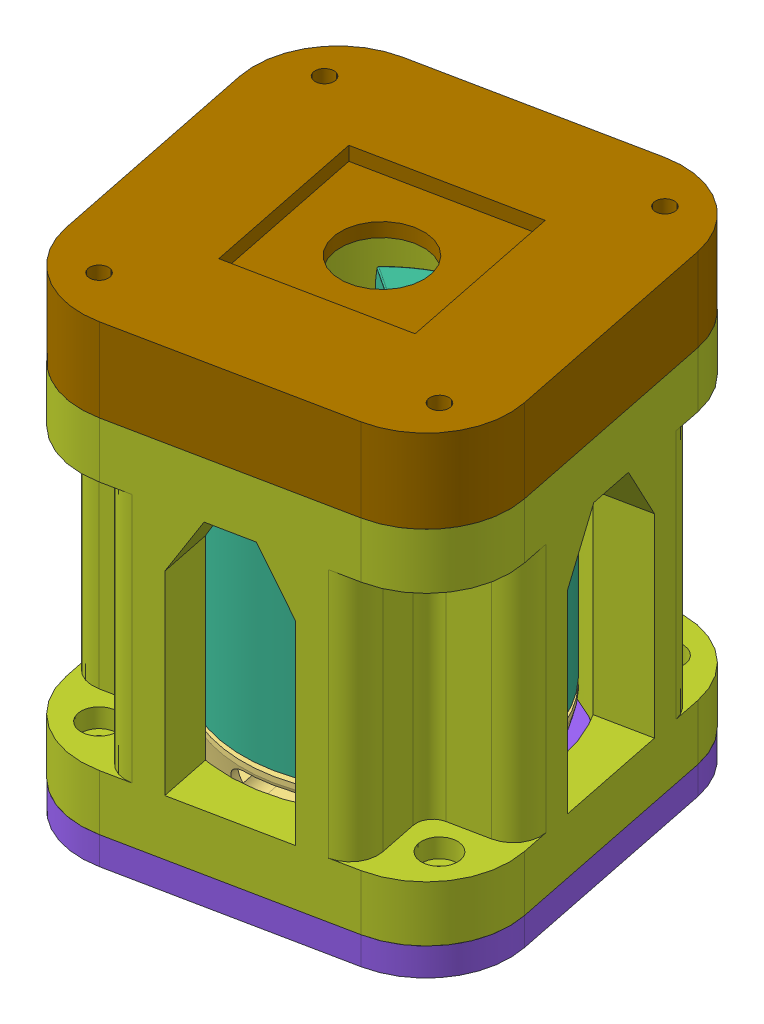
SolidWorks assembly Cheap 5065, configuration Default. Lengths in mm.
Overall size (82.53 103.1 82.53).
119 component instances, 9 part files, 14 mates.
Components (placement in the parent):
- Cheap 5065.step-1: Cheap 5065.step [Default] at (0 82 0) x (0.199009 0 0.979998) z (-0.979998 0 0.199009) size (50 84 50)
  - Stator.step-1: Stator.step [Default] at (0 -45.9 0) size (40 38 40)
    - Coils.step-1: Coils.step [Default] at origin size (4.5 38 8)
      - Copper Coil.step-1: Copper Coil.step [Default] at (0 0 -0.5) size (4.5 38 1)
      - Copper Coil.step-2: Copper Coil.step [Default] at (0 0 -2.5) size (4.5 38 1)
      - Copper Coil.step-3: Copper Coil.step [Default] at (0 0 -6.5) size (4.5 38 1)
      - Copper Coil.step-4: Copper Coil.step [Default] at (0 0 -1.5) size (4.5 38 1)
      - Copper Coil.step-5: Copper Coil.step [Default] at (0 0 -4.5) size (4.5 38 1)
      - Copper Coil.step-6: Copper Coil.step [Default] at (0 0 -7.5) size (4.5 38 1)
      - Copper Coil.step-7: Copper Coil.step [Default] at (0 0 -3.5) size (4.5 38 1)
      - Copper Coil.step-8: Copper Coil.step [Default] at (0 0 -5.5) size (4.5 38 1)
    - Coils.step-2: Coils.step [Default] x (0.866025 0 -0.5) z (0.5 0 0.866025) size (4.5 38 8)
      - Copper Coil.step-1: Copper Coil.step [Default] at (0 0 -0.5) size (4.5 38 1)
      - Copper Coil.step-2: Copper Coil.step [Default] at (0 0 -2.5) size (4.5 38 1)
      - Copper Coil.step-3: Copper Coil.step [Default] at (0 0 -6.5) size (4.5 38 1)
      - Copper Coil.step-4: Copper Coil.step [Default] at (0 0 -1.5) size (4.5 38 1)
      - Copper Coil.step-5: Copper Coil.step [Default] at (0 0 -4.5) size (4.5 38 1)
      - Copper Coil.step-6: Copper Coil.step [Default] at (0 0 -7.5) size (4.5 38 1)
      - Copper Coil.step-7: Copper Coil.step [Default] at (0 0 -3.5) size (4.5 38 1)
      - Copper Coil.step-8: Copper Coil.step [Default] at (0 0 -5.5) size (4.5 38 1)
    - Coils.step-3: Coils.step [Default] x (0.5 0 -0.866025) z (0.866025 0 0.5) size (4.5 38 8)
      - Copper Coil.step-1: Copper Coil.step [Default] at (0 0 -0.5) size (4.5 38 1)
      - Copper Coil.step-2: Copper Coil.step [Default] at (0 0 -2.5) size (4.5 38 1)
      - Copper Coil.step-3: Copper Coil.step [Default] at (0 0 -6.5) size (4.5 38 1)
      - Copper Coil.step-4: Copper Coil.step [Default] at (0 0 -1.5) size (4.5 38 1)
      - Copper Coil.step-5: Copper Coil.step [Default] at (0 0 -4.5) size (4.5 38 1)
      - Copper Coil.step-6: Copper Coil.step [Default] at (0 0 -7.5) size (4.5 38 1)
      - Copper Coil.step-7: Copper Coil.step [Default] at (0 0 -3.5) size (4.5 38 1)
      - Copper Coil.step-8: Copper Coil.step [Default] at (0 0 -5.5) size (4.5 38 1)
    - Coils.step-4: Coils.step [Default] x (0 0 -1) z (1 0 0) size (4.5 38 8)
      - Copper Coil.step-1: Copper Coil.step [Default] at (0 0 -0.5) size (4.5 38 1)
      - Copper Coil.step-2: Copper Coil.step [Default] at (0 0 -2.5) size (4.5 38 1)
      - Copper Coil.step-3: Copper Coil.step [Default] at (0 0 -6.5) size (4.5 38 1)
      - Copper Coil.step-4: Copper Coil.step [Default] at (0 0 -1.5) size (4.5 38 1)
      - Copper Coil.step-5: Copper Coil.step [Default] at (0 0 -4.5) size (4.5 38 1)
      - Copper Coil.step-6: Copper Coil.step [Default] at (0 0 -7.5) size (4.5 38 1)
      - Copper Coil.step-7: Copper Coil.step [Default] at (0 0 -3.5) size (4.5 38 1)
      - Copper Coil.step-8: Copper Coil.step [Default] at (0 0 -5.5) size (4.5 38 1)
    - Coils.step-5: Coils.step [Default] x (-0.5 0 -0.866025) z (0.866025 0 -0.5) size (4.5 38 8)
      - Copper Coil.step-1: Copper Coil.step [Default] at (0 0 -0.5) size (4.5 38 1)
      - Copper Coil.step-2: Copper Coil.step [Default] at (0 0 -2.5) size (4.5 38 1)
      - Copper Coil.step-3: Copper Coil.step [Default] at (0 0 -6.5) size (4.5 38 1)
      - Copper Coil.step-4: Copper Coil.step [Default] at (0 0 -1.5) size (4.5 38 1)
      - Copper Coil.step-5: Copper Coil.step [Default] at (0 0 -4.5) size (4.5 38 1)
      - Copper Coil.step-6: Copper Coil.step [Default] at (0 0 -7.5) size (4.5 38 1)
      - Copper Coil.step-7: Copper Coil.step [Default] at (0 0 -3.5) size (4.5 38 1)
      - Copper Coil.step-8: Copper Coil.step [Default] at (0 0 -5.5) size (4.5 38 1)
    - Coils.step-6: Coils.step [Default] x (-0.866025 0 -0.5) z (0.5 0 -0.866025) size (4.5 38 8)
      - Copper Coil.step-1: Copper Coil.step [Default] at (0 0 -0.5) size (4.5 38 1)
      - Copper Coil.step-2: Copper Coil.step [Default] at (0 0 -2.5) size (4.5 38 1)
      - Copper Coil.step-3: Copper Coil.step [Default] at (0 0 -6.5) size (4.5 38 1)
      - Copper Coil.step-4: Copper Coil.step [Default] at (0 0 -1.5) size (4.5 38 1)
      - Copper Coil.step-5: Copper Coil.step [Default] at (0 0 -4.5) size (4.5 38 1)
      - Copper Coil.step-6: Copper Coil.step [Default] at (0 0 -7.5) size (4.5 38 1)
      - Copper Coil.step-7: Copper Coil.step [Default] at (0 0 -3.5) size (4.5 38 1)
      - Copper Coil.step-8: Copper Coil.step [Default] at (0 0 -5.5) size (4.5 38 1)
    - Coils.step-7: Coils.step [Default] x (-1 0 0) z (0 0 -1) size (4.5 38 8)
      - Copper Coil.step-1: Copper Coil.step [Default] at (0 0 -0.5) size (4.5 38 1)
      - Copper Coil.step-2: Copper Coil.step [Default] at (0 0 -2.5) size (4.5 38 1)
      - Copper Coil.step-3: Copper Coil.step [Default] at (0 0 -6.5) size (4.5 38 1)
      - Copper Coil.step-4: Copper Coil.step [Default] at (0 0 -1.5) size (4.5 38 1)
      - Copper Coil.step-5: Copper Coil.step [Default] at (0 0 -4.5) size (4.5 38 1)
      - Copper Coil.step-6: Copper Coil.step [Default] at (0 0 -7.5) size (4.5 38 1)
      - Copper Coil.step-7: Copper Coil.step [Default] at (0 0 -3.5) size (4.5 38 1)
      - Copper Coil.step-8: Copper Coil.step [Default] at (0 0 -5.5) size (4.5 38 1)
    - Coils.step-8: Coils.step [Default] x (-0.866025 0 0.5) z (-0.5 0 -0.866025) size (4.5 38 8)
      - Copper Coil.step-1: Copper Coil.step [Default] at (0 0 -0.5) size (4.5 38 1)
      - Copper Coil.step-2: Copper Coil.step [Default] at (0 0 -2.5) size (4.5 38 1)
      - Copper Coil.step-3: Copper Coil.step [Default] at (0 0 -6.5) size (4.5 38 1)
      - Copper Coil.step-4: Copper Coil.step [Default] at (0 0 -1.5) size (4.5 38 1)
      - Copper Coil.step-5: Copper Coil.step [Default] at (0 0 -4.5) size (4.5 38 1)
      - Copper Coil.step-6: Copper Coil.step [Default] at (0 0 -7.5) size (4.5 38 1)
      - Copper Coil.step-7: Copper Coil.step [Default] at (0 0 -3.5) size (4.5 38 1)
      - Copper Coil.step-8: Copper Coil.step [Default] at (0 0 -5.5) size (4.5 38 1)
    - Coils.step-9: Coils.step [Default] x (-0.5 0 0.866025) z (-0.866025 0 -0.5) size (4.5 38 8)
      - Copper Coil.step-1: Copper Coil.step [Default] at (0 0 -0.5) size (4.5 38 1)
      - Copper Coil.step-2: Copper Coil.step [Default] at (0 0 -2.5) size (4.5 38 1)
      - Copper Coil.step-3: Copper Coil.step [Default] at (0 0 -6.5) size (4.5 38 1)
      - Copper Coil.step-4: Copper Coil.step [Default] at (0 0 -1.5) size (4.5 38 1)
      - Copper Coil.step-5: Copper Coil.step [Default] at (0 0 -4.5) size (4.5 38 1)
      - Copper Coil.step-6: Copper Coil.step [Default] at (0 0 -7.5) size (4.5 38 1)
      - Copper Coil.step-7: Copper Coil.step [Default] at (0 0 -3.5) size (4.5 38 1)
      - Copper Coil.step-8: Copper Coil.step [Default] at (0 0 -5.5) size (4.5 38 1)
    - Coils.step-10: Coils.step [Default] x (0 0 1) z (-1 0 0) size (4.5 38 8)
      - Copper Coil.step-1: Copper Coil.step [Default] at (0 0 -0.5) size (4.5 38 1)
      - Copper Coil.step-2: Copper Coil.step [Default] at (0 0 -2.5) size (4.5 38 1)
      - Copper Coil.step-3: Copper Coil.step [Default] at (0 0 -6.5) size (4.5 38 1)
      - Copper Coil.step-4: Copper Coil.step [Default] at (0 0 -1.5) size (4.5 38 1)
      - Copper Coil.step-5: Copper Coil.step [Default] at (0 0 -4.5) size (4.5 38 1)
      - Copper Coil.step-6: Copper Coil.step [Default] at (0 0 -7.5) size (4.5 38 1)
      - Copper Coil.step-7: Copper Coil.step [Default] at (0 0 -3.5) size (4.5 38 1)
      - Copper Coil.step-8: Copper Coil.step [Default] at (0 0 -5.5) size (4.5 38 1)
    - Coils.step-11: Coils.step [Default] x (0.5 0 0.866025) z (-0.866025 0 0.5) size (4.5 38 8)
      - Copper Coil.step-1: Copper Coil.step [Default] at (0 0 -0.5) size (4.5 38 1)
      - Copper Coil.step-2: Copper Coil.step [Default] at (0 0 -2.5) size (4.5 38 1)
      - Copper Coil.step-3: Copper Coil.step [Default] at (0 0 -6.5) size (4.5 38 1)
      - Copper Coil.step-4: Copper Coil.step [Default] at (0 0 -1.5) size (4.5 38 1)
      - Copper Coil.step-5: Copper Coil.step [Default] at (0 0 -4.5) size (4.5 38 1)
      - Copper Coil.step-6: Copper Coil.step [Default] at (0 0 -7.5) size (4.5 38 1)
      - Copper Coil.step-7: Copper Coil.step [Default] at (0 0 -3.5) size (4.5 38 1)
      - Copper Coil.step-8: Copper Coil.step [Default] at (0 0 -5.5) size (4.5 38 1)
    - Coils.step-12: Coils.step [Default] x (0.866025 0 0.5) z (-0.5 0 0.866025) size (4.5 38 8)
      - Copper Coil.step-1: Copper Coil.step [Default] at (0 0 -0.5) size (4.5 38 1)
      - Copper Coil.step-2: Copper Coil.step [Default] at (0 0 -2.5) size (4.5 38 1)
      - Copper Coil.step-3: Copper Coil.step [Default] at (0 0 -6.5) size (4.5 38 1)
      - Copper Coil.step-4: Copper Coil.step [Default] at (0 0 -1.5) size (4.5 38 1)
      - Copper Coil.step-5: Copper Coil.step [Default] at (0 0 -4.5) size (4.5 38 1)
      - Copper Coil.step-6: Copper Coil.step [Default] at (0 0 -7.5) size (4.5 38 1)
      - Copper Coil.step-7: Copper Coil.step [Default] at (0 0 -3.5) size (4.5 38 1)
      - Copper Coil.step-8: Copper Coil.step [Default] at (0 0 -5.5) size (4.5 38 1)
    - Stator-0.step-1: Stator-0.step [Default] at origin size (40 35 40)
  - Stator Base.step-1: Stator Base.step [Default] at (0 -58.9 0) size (50 13.01 50)
  - 7804K117_Stainless Steel Ball Bearing.step-1: 7804K117_Stainless Steel Ball Bearing.step [Default] at (0 -54.9 0) x (1 0 0) z (0 -1 0) size (16 16 5)
  - 7804K117_Stainless Steel Ball Bearing.step-2: 7804K117_Stainless Steel Ball Bearing.step [Default] at (0 -14.9 0) x (1 0 0) z (0 -1 0) size (16 16 5)
  - Shaft.step-1: Shaft.step [Default] at (0 -82 0) size (8 84 8)
  - Rotor.step-1: Rotor.step [Default] at origin size (50 49 50)
- Part8^Cheap 5065-1: Part8^Cheap 5065 [Default] at (0 23.1 0) x (-0.199009 0 -0.979998) z (0.979998 0 -0.199009) size (70 65 70) (virtual)
- Part9^Cheap 5065-1: Part9^Cheap 5065 [Default] at (0 23.1 0) x (0.199009 0 0.979998) z (0 -1 0) size (70 70 5) (virtual)
- Part10^Cheap 5065-1: Part10^Cheap 5065 [Default] at (0 88.1 0) x (-0.199009 0 -0.979998) z (0 1 0) size (70 70 15) (virtual)
Mates (geometry in assembly coordinates):
- Concentric1: concentric: cylinder of Cheap 5065.step-1/Rotor.step-1 through (0 75 0) axis (0 -1 0) radius 25
- Parallel2: parallel aligned: plane of Cheap 5065.step-1 through (0 82 0) normal (0 1 0)
- Coincident11: coincident anti-aligned: plane of Cheap 5065.step-1/Shaft.step-1 through (0 0 0) normal (0 -1 0)
- Coincident12: coincident aligned: plane of Cheap 5065.step-1/Stator Base.step-1 through (0 23.1 0) normal (0 -1 0); plane of Part8^Cheap 5065-1 through (0 23.1 0) normal (0 -1 0)
- Concentric2: concentric aligned: cylinder of Cheap 5065.step-1/Shaft.step-1 through (0 0 0) axis (0 1 0) radius 4; cylinder of Part8^Cheap 5065-1 through (0 23.1 0) axis (0 1 0) radius 27.5
- Coincident18: coincident aligned: plane of Part8^Cheap 5065-1 through (41.2652 88.1 27.3346) normal (0.979998 0 -0.199009); plane of Part9^Cheap 5065-1 through (27.3346 18.1 -41.2652) normal (0.979998 0 -0.199009)
- Coincident19: coincident aligned: plane of Part8^Cheap 5065-1 through (-27.3346 88.1 41.2652) normal (0.199009 0 0.979998); plane of Part9^Cheap 5065-1 through (-27.3346 18.1 41.2652) normal (0.199009 0 0.979998)
- Coincident22: coincident anti-aligned: plane of Part8^Cheap 5065-1 through (0 23.1 0) normal (0 -1 0); plane of Part9^Cheap 5065-1 through (0 23.1 0) normal (0 1 0)
- Parallel4: parallel aligned: plane of Part10^Cheap 5065-1 through (-41.2652 103.1 -27.3346) normal (-0.199009 0 -0.979998); plane of Part8^Cheap 5065-1 through (-41.2652 88.1 -27.3346) normal (-0.199009 0 -0.979998)
- Coincident27: coincident aligned: plane of Part8^Cheap 5065-1 through (41.2652 88.1 27.3346) normal (0.979998 0 -0.199009); plane of Part10^Cheap 5065-1 through (27.3346 103.1 -41.2652) normal (0.979998 0 -0.199009)
- Concentric3: concentric anti-aligned: cylinder of Cheap 5065.step-1/Stator Base.step-1 through (8.2836 23.1 -12.5053) axis (0 1 0) radius 2; cylinder of Part9^Cheap 5065-1 through (8.2836 18.1 -12.5053) axis (0 -1 0) radius 1.7
- Coincident28: coincident aligned: plane of Part8^Cheap 5065-1 through (-27.3346 88.1 41.2652) normal (-0.979998 0 0.199009); plane of Part10^Cheap 5065-1 through (-41.2652 103.1 -27.3346) normal (-0.979998 0 0.199009)
- Coincident29: coincident aligned: plane of Part8^Cheap 5065-1 through (-41.2652 88.1 -27.3346) normal (-0.199009 0 -0.979998); plane of Part10^Cheap 5065-1 through (-41.2652 103.1 -27.3346) normal (-0.199009 0 -0.979998)
- Coincident30: coincident anti-aligned: plane of Part8^Cheap 5065-1 through (0 88.1 0) normal (0 1 0); plane of Part10^Cheap 5065-1 through (0 88.1 0) normal (0 -1 0)
